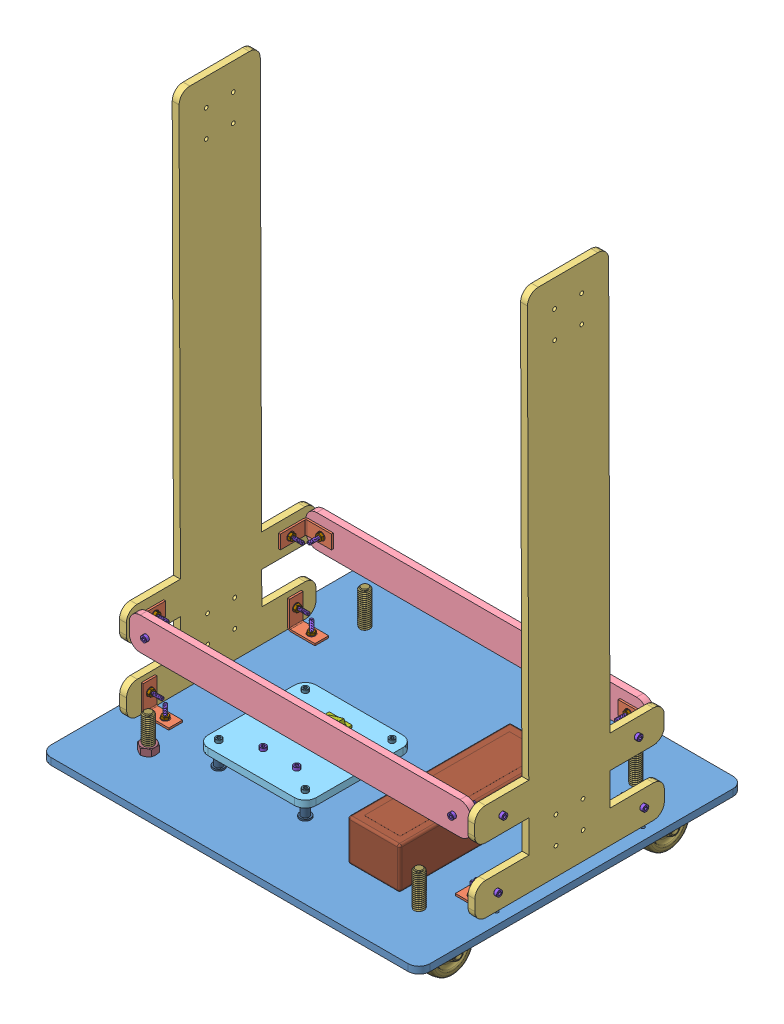
SolidWorks assembly Assembly_bottom, configuration Default. Lengths in mm.
Overall size (350 542.4 300).
72 component instances, 14 part files, 86 mates.
Components (placement in the parent):
- Base-1: Base [Default] at (92.1268 196.2606 279.7334) size (350 6.35 300)
- 1556A410_BRACKET-1: 1556A410_BRACKET [1556A41] at (-65.5682 202.6106 212.2334) x (1 0 0) z (0 1 0) size (25.4 12.7 25.4)
- 1556A410_BRACKET-2: 1556A410_BRACKET [1556A41] at (-65.5682 202.6106 347.2334) x (1 0 0) z (0 1 0) size (25.4 12.7 25.4)
- 1556A410_BRACKET-3: 1556A410_BRACKET [1556A41] at (249.8218 202.6106 212.2334) x (-1 0 0) z (0 1 0) size (25.4 12.7 25.4)
- 1556A410_BRACKET-4: 1556A410_BRACKET [1556A41] at (249.8218 202.6106 347.2334) x (-1 0 0) z (0 1 0) size (25.4 12.7 25.4)
- Part3-1: Part3 [Default] at (-71.9182 442.8211 280.453) x (0 -0.999995 -0.003209) z (0 -0.003209 0.999995) size (480 6.35 175)
- Part3-2: Part3 [Default] at (256.1718 442.8211 280.453) x (0 -0.999995 -0.003209) z (0 0.003209 -0.999995) size (480 6.35 175)
- 1556A410_BRACKET-5: 1556A410_BRACKET [1556A41] at (-65.5682 278.0225 201.5488) size (25.4 12.7 25.4)
- 1556A410_BRACKET-8: 1556A410_BRACKET [1556A41] at (-65.5682 277.6213 358.2981) x (1 0 0) z (0 0 -1) size (25.4 12.7 25.4)
- 1556A410_BRACKET-9: 1556A410_BRACKET [1556A41] at (249.8218 277.6213 358.2981) x (-1 0 0) z (0 0 -1) size (25.4 12.7 25.4)
- 1556A410_BRACKET-10: 1556A410_BRACKET [1556A41] at (249.8218 278.0225 201.5488) x (0 0 1) z (-1 0 0) size (25.4 12.7 25.4)
- Part4-1: Part4 [Default] at (92.1318 278.0225 201.5488) x (1 0 0) z (0 1 0) size (315.39 6.35 30)
- Part4-3: Part4 [Default] at (92.1318 277.6213 358.2981) x (1 0 0) z (0 -1 0) size (315.39 6.35 30)
- Circuit_base-3: Circuit_base [Default] at (52.1268 216.6106 319.7334) size (100 6.35 100)
- circuit-1: circuit [Default] at (54.6268 216.6106 330.2334) x (-1 0 0) z (0 0 1) size (36 3 36)
- switch-2: switch [Default] at (52.2268 222.9606 294.7334) size (21.2 26.4 15.1)
- 91290A123_BLACK-OXIDE CLASS 12.9 SOCKET HEAD CAP SCREW-1: 91290A123_BLACK-OXIDE CLASS 12.9 SOCKET HEAD CAP SCREW [91290A123] at (-51.9182 218.4856 347.2334) x (0 0 -1) z (1 0 0) size (5.5 5.5 23.27)
- 91290A123_BLACK-OXIDE CLASS 12.9 SOCKET HEAD CAP SCREW-2: 91290A123_BLACK-OXIDE CLASS 12.9 SOCKET HEAD CAP SCREW [91290A123] at (-51.9182 218.9188 212.2341) x (0 0 -1) z (1 0 0) size (5.5 5.5 23.27)
- 91290A123_BLACK-OXIDE CLASS 12.9 SOCKET HEAD CAP SCREW-3: 91290A123_BLACK-OXIDE CLASS 12.9 SOCKET HEAD CAP SCREW [91290A123] at (236.1718 218.4856 347.2334) x (0 0 1) z (-1 0 0) size (5.5 5.5 23.27)
- 91290A123_BLACK-OXIDE CLASS 12.9 SOCKET HEAD CAP SCREW-6: 91290A123_BLACK-OXIDE CLASS 12.9 SOCKET HEAD CAP SCREW [91290A123] at (236.1718 218.9188 212.2341) x (0 0 1) z (-1 0 0) size (5.5 5.5 23.27)
- 91290A123_BLACK-OXIDE CLASS 12.9 SOCKET HEAD CAP SCREW-7: 91290A123_BLACK-OXIDE CLASS 12.9 SOCKET HEAD CAP SCREW [91290A123] at (233.9468 216.2606 347.2334) x (-0.837169 0 -0.546944) z (0 1 0) size (5.5 5.5 23.27)
- 91290A123_BLACK-OXIDE CLASS 12.9 SOCKET HEAD CAP SCREW-8: 91290A123_BLACK-OXIDE CLASS 12.9 SOCKET HEAD CAP SCREW [91290A123] at (233.9468 216.2606 212.2334) x (-0.837169 0 -0.546944) z (0 1 0) size (5.5 5.5 23.27)
- 91290A123_BLACK-OXIDE CLASS 12.9 SOCKET HEAD CAP SCREW-9: 91290A123_BLACK-OXIDE CLASS 12.9 SOCKET HEAD CAP SCREW [91290A123] at (-49.6932 216.2606 347.2334) x (-0.837169 0 -0.546944) z (0 1 0) size (5.5 5.5 23.27)
- 91290A123_BLACK-OXIDE CLASS 12.9 SOCKET HEAD CAP SCREW-10: 91290A123_BLACK-OXIDE CLASS 12.9 SOCKET HEAD CAP SCREW [91290A123] at (-49.6932 216.2606 212.2334) x (-0.837169 0 -0.546944) z (0 1 0) size (5.5 5.5 23.27)
- 91290A123_BLACK-OXIDE CLASS 12.9 SOCKET HEAD CAP SCREW-11: 91290A123_BLACK-OXIDE CLASS 12.9 SOCKET HEAD CAP SCREW [91290A123] at (-49.6832 278.0225 215.1988) size (5.5 5.5 23.27)
- 91290A123_BLACK-OXIDE CLASS 12.9 SOCKET HEAD CAP SCREW-13: 91290A123_BLACK-OXIDE CLASS 12.9 SOCKET HEAD CAP SCREW [91290A123] at (233.9568 278.0225 215.1988) size (5.5 5.5 23.27)
- 91290A123_BLACK-OXIDE CLASS 12.9 SOCKET HEAD CAP SCREW-14: 91290A123_BLACK-OXIDE CLASS 12.9 SOCKET HEAD CAP SCREW [91290A123] at (233.9468 277.6213 344.6481) x (1 0 0) z (0 0 -1) size (5.5 5.5 23.27)
- 91290A123_BLACK-OXIDE CLASS 12.9 SOCKET HEAD CAP SCREW-15: 91290A123_BLACK-OXIDE CLASS 12.9 SOCKET HEAD CAP SCREW [91290A123] at (-49.6932 277.6213 344.6481) x (1 0 0) z (0 0 -1) size (5.5 5.5 23.27)
- 91290A123_BLACK-OXIDE CLASS 12.9 SOCKET HEAD CAP SCREW-16: 91290A123_BLACK-OXIDE CLASS 12.9 SOCKET HEAD CAP SCREW [91290A123] at (-51.9182 278.0225 217.4238) x (0 0 -1) z (1 0 0) size (5.5 5.5 23.27)
- 91290A123_BLACK-OXIDE CLASS 12.9 SOCKET HEAD CAP SCREW-17: 91290A123_BLACK-OXIDE CLASS 12.9 SOCKET HEAD CAP SCREW [91290A123] at (-51.9182 277.6213 342.4231) x (0 0 -1) z (1 0 0) size (5.5 5.5 23.27)
- 91290A123_BLACK-OXIDE CLASS 12.9 SOCKET HEAD CAP SCREW-18: 91290A123_BLACK-OXIDE CLASS 12.9 SOCKET HEAD CAP SCREW [91290A123] at (236.1718 277.6213 342.4231) x (0 0 -1) z (-1 0 0) size (5.5 5.5 23.27)
- 91290A123_BLACK-OXIDE CLASS 12.9 SOCKET HEAD CAP SCREW-19: 91290A123_BLACK-OXIDE CLASS 12.9 SOCKET HEAD CAP SCREW [91290A123] at (236.1718 278.0225 217.4238) x (0 0 -1) z (-1 0 0) size (5.5 5.5 23.27)
- 92497A200_ZINC YELLOW-CHROMATE PLATED STEEL HEX NUT-2: 92497A200_ZINC YELLOW-CHROMATE PLATED STEEL HEX NUT [92497A200] at (-49.6932 278.0225 204.5268) size (5.5 6.35 2.78)
- 92497A200_ZINC YELLOW-CHROMATE PLATED STEEL HEX NUT-3: 92497A200_ZINC YELLOW-CHROMATE PLATED STEEL HEX NUT [92497A200] at (234.1068 278.0225 204.5268) size (5.5 6.35 2.78)
- 92497A200_ZINC YELLOW-CHROMATE PLATED STEEL HEX NUT-4: 92497A200_ZINC YELLOW-CHROMATE PLATED STEEL HEX NUT [92497A200] at (233.9468 277.6213 355.3201) size (5.5 6.35 2.78)
- 92497A200_ZINC YELLOW-CHROMATE PLATED STEEL HEX NUT-5: 92497A200_ZINC YELLOW-CHROMATE PLATED STEEL HEX NUT [92497A200] at (-49.8532 277.6213 355.3201) size (5.5 6.35 2.78)
- 92497A200_ZINC YELLOW-CHROMATE PLATED STEEL HEX NUT-7: 92497A200_ZINC YELLOW-CHROMATE PLATED STEEL HEX NUT [92497A200] at (-49.6932 205.5886 347.2334) x (0.837169 0 0.546944) z (0 1 0) size (5.5 6.35 2.78)
- 92497A200_ZINC YELLOW-CHROMATE PLATED STEEL HEX NUT-8: 92497A200_ZINC YELLOW-CHROMATE PLATED STEEL HEX NUT [92497A200] at (-49.6932 205.5886 212.2334) x (0.837169 0 0.546944) z (0 1 0) size (5.5 6.35 2.78)
- 92497A200_ZINC YELLOW-CHROMATE PLATED STEEL HEX NUT-9: 92497A200_ZINC YELLOW-CHROMATE PLATED STEEL HEX NUT [92497A200] at (233.9468 205.5886 347.2334) x (-0.837169 0 -0.546944) z (0 1 0) size (5.5 6.35 2.78)
- 92497A200_ZINC YELLOW-CHROMATE PLATED STEEL HEX NUT-11: 92497A200_ZINC YELLOW-CHROMATE PLATED STEEL HEX NUT [92497A200] at (233.9468 205.5886 212.2334) x (-0.837169 0 -0.546944) z (0 1 0) size (5.5 6.35 2.78)
- 92497A200_ZINC YELLOW-CHROMATE PLATED STEEL HEX NUT-12: 92497A200_ZINC YELLOW-CHROMATE PLATED STEEL HEX NUT [92497A200] at (-62.5902 218.4856 212.2334) x (0 0.381849 -0.924225) z (1 0 0) size (5.5 6.35 2.78)
- 92497A200_ZINC YELLOW-CHROMATE PLATED STEEL HEX NUT-13: 92497A200_ZINC YELLOW-CHROMATE PLATED STEEL HEX NUT [92497A200] at (-62.5902 218.4856 347.2334) x (0 0.381849 -0.924225) z (1 0 0) size (5.5 6.35 2.78)
- 92497A200_ZINC YELLOW-CHROMATE PLATED STEEL HEX NUT-14: 92497A200_ZINC YELLOW-CHROMATE PLATED STEEL HEX NUT [92497A200] at (246.8438 277.6213 342.4231) x (0 1 0) z (-1 0 0) size (5.5 6.35 2.78)
- 92497A200_ZINC YELLOW-CHROMATE PLATED STEEL HEX NUT-15: 92497A200_ZINC YELLOW-CHROMATE PLATED STEEL HEX NUT [92497A200] at (-62.5902 277.6213 342.4231) x (0 0 -1) z (1 0 0) size (5.5 6.35 2.78)
- 92497A200_ZINC YELLOW-CHROMATE PLATED STEEL HEX NUT-16: 92497A200_ZINC YELLOW-CHROMATE PLATED STEEL HEX NUT [92497A200] at (-62.5902 278.0225 217.4238) x (0 0 -1) z (1 0 0) size (5.5 6.35 2.78)
- 92497A200_ZINC YELLOW-CHROMATE PLATED STEEL HEX NUT-17: 92497A200_ZINC YELLOW-CHROMATE PLATED STEEL HEX NUT [92497A200] at (246.8438 278.0225 217.4238) x (0 1 0) z (-1 0 0) size (5.5 6.35 2.78)
- 91290A123_BLACK-OXIDE CLASS 12.9 SOCKET HEAD CAP SCREW-20: 91290A123_BLACK-OXIDE CLASS 12.9 SOCKET HEAD CAP SCREW [91290A123] at (39.1268 202.9606 345.7334) x (1 0 0) z (0 -1 0) size (5.5 5.5 23.27)
- 92497A200_ZINC YELLOW-CHROMATE PLATED STEEL HEX NUT-22: 92497A200_ZINC YELLOW-CHROMATE PLATED STEEL HEX NUT [92497A200] at (39.1268 214.4106 345.7334) x (1 0 0) z (0 -1 0) size (5.5 6.35 2.78)
- 91290A123_BLACK-OXIDE CLASS 12.9 SOCKET HEAD CAP SCREW-21: 91290A123_BLACK-OXIDE CLASS 12.9 SOCKET HEAD CAP SCREW [91290A123] at (70.1268 202.9606 345.7334) x (1 0 0) z (0 -1 0) size (5.5 5.5 23.27)
- 91290A123_BLACK-OXIDE CLASS 12.9 SOCKET HEAD CAP SCREW-22: 91290A123_BLACK-OXIDE CLASS 12.9 SOCKET HEAD CAP SCREW [91290A123] at (39.1268 202.9606 314.7334) x (1 0 0) z (0 -1 0) size (5.5 5.5 23.27)
- 91290A123_BLACK-OXIDE CLASS 12.9 SOCKET HEAD CAP SCREW-23: 91290A123_BLACK-OXIDE CLASS 12.9 SOCKET HEAD CAP SCREW [91290A123] at (70.1268 202.9606 314.7334) x (1 0 0) z (0 -1 0) size (5.5 5.5 23.27)
- 92497A200_ZINC YELLOW-CHROMATE PLATED STEEL HEX NUT-23: 92497A200_ZINC YELLOW-CHROMATE PLATED STEEL HEX NUT [92497A200] at (70.1268 214.4106 345.7334) x (1 0 0) z (0 -1 0) size (5.5 6.35 2.78)
- 92497A200_ZINC YELLOW-CHROMATE PLATED STEEL HEX NUT-24: 92497A200_ZINC YELLOW-CHROMATE PLATED STEEL HEX NUT [92497A200] at (39.1268 214.4106 314.7334) x (1 0 0) z (0 -1 0) size (5.5 6.35 2.78)
- 92497A200_ZINC YELLOW-CHROMATE PLATED STEEL HEX NUT-25: 92497A200_ZINC YELLOW-CHROMATE PLATED STEEL HEX NUT [92497A200] at (70.1268 214.4106 314.7334) x (1 0 0) z (0 -1 0) size (5.5 6.35 2.78)
- circuit_base_spacer-5: circuit_base_spacer [Default] at (12.1268 202.6106 359.7334) size (10 14 10)
- circuit_base_spacer-6: circuit_base_spacer [Default] at (12.1268 202.6106 279.7334) size (10 14 10)
- circuit_base_spacer-7: circuit_base_spacer [Default] at (92.1268 202.6106 359.7334) size (10 14 10)
- circuit_base_spacer-8: circuit_base_spacer [Default] at (92.1268 202.6106 279.7334) size (10 14 10)
- battery-2: battery [Default] at (172.8881 202.6106 302.4714) x (0 0 -1) z (1 0 0) size (150 38.05 48)
- 2834T110_THREADED-STEM SWIVEL CASTER-2: 2834T110_THREADED-STEM SWIVEL CASTER [2834T11] at (-32.8732 215.3106 379.7334) x (0 0 -1) z (1 0 0) size (58.52 93.93 32.91)
- 2834T110_THREADED-STEM SWIVEL CASTER-3: 2834T110_THREADED-STEM SWIVEL CASTER [2834T11] at (217.1268 215.3106 379.7334) x (0 0 -1) z (1 0 0) size (58.52 93.93 32.91)
- 2834T110_THREADED-STEM SWIVEL CASTER-4: 2834T110_THREADED-STEM SWIVEL CASTER [2834T11] at (-32.8732 215.3106 179.7334) x (0 0 -1) z (1 0 0) size (58.52 93.93 32.91)
- 2834T110_THREADED-STEM SWIVEL CASTER-5: 2834T110_THREADED-STEM SWIVEL CASTER [2834T11] at (217.1268 215.3106 179.7334) x (0 0 -1) z (1 0 0) size (58.52 93.93 32.91)
- 90591A161_ZINC PLATED STEEL HEX NUT-1: 90591A161_ZINC PLATED STEEL HEX NUT [90591A161] at (-32.8732 205.8606 379.7334) x (1 0 0) z (0 -1 0) size (13 15.01 7.38)
- 91290A171_BLACK-OXIDE CLASS 12.9 SOCKET HEAD CAP SCREW-5: 91290A171_BLACK-OXIDE CLASS 12.9 SOCKET HEAD CAP SCREW [91290A171] at (12.1268 192.9606 359.7334) x (1 0 0) z (0 -1 0) size (5.5 5.5 33.33)
- 91290A171_BLACK-OXIDE CLASS 12.9 SOCKET HEAD CAP SCREW-6: 91290A171_BLACK-OXIDE CLASS 12.9 SOCKET HEAD CAP SCREW [91290A171] at (92.1268 192.9606 359.7334) x (1 0 0) z (0 -1 0) size (5.5 5.5 33.33)
- 91290A171_BLACK-OXIDE CLASS 12.9 SOCKET HEAD CAP SCREW-7: 91290A171_BLACK-OXIDE CLASS 12.9 SOCKET HEAD CAP SCREW [91290A171] at (12.1268 192.9606 279.7334) x (1 0 0) z (0 -1 0) size (5.5 5.5 33.33)
- 91290A171_BLACK-OXIDE CLASS 12.9 SOCKET HEAD CAP SCREW-8: 91290A171_BLACK-OXIDE CLASS 12.9 SOCKET HEAD CAP SCREW [91290A171] at (92.1268 192.9606 279.7334) x (1 0 0) z (0 -1 0) size (5.5 5.5 33.33)
- 92497A200_ZINC YELLOW-CHROMATE PLATED STEEL HEX NUT-28: 92497A200_ZINC YELLOW-CHROMATE PLATED STEEL HEX NUT [92497A200] at (12.1268 195.0606 359.7334) x (0.837169 0 0.546944) z (0 1 0) size (5.5 6.35 2.78)
- 92497A200_ZINC YELLOW-CHROMATE PLATED STEEL HEX NUT-29: 92497A200_ZINC YELLOW-CHROMATE PLATED STEEL HEX NUT [92497A200] at (92.1268 195.0606 359.7334) x (0.837169 0 0.546944) z (0 1 0) size (5.5 6.35 2.78)
- 92497A200_ZINC YELLOW-CHROMATE PLATED STEEL HEX NUT-30: 92497A200_ZINC YELLOW-CHROMATE PLATED STEEL HEX NUT [92497A200] at (12.1268 195.0606 279.7334) x (0.837169 0 0.546944) z (0 1 0) size (5.5 6.35 2.78)
- 92497A200_ZINC YELLOW-CHROMATE PLATED STEEL HEX NUT-31: 92497A200_ZINC YELLOW-CHROMATE PLATED STEEL HEX NUT [92497A200] at (92.1268 195.0606 279.7334) x (0.837169 0 0.546944) z (0 1 0) size (5.5 6.35 2.78)
Mates (geometry in assembly coordinates):
- Concentric1: concentric anti-aligned: circle of Base-1; circle of 1556A410_BRACKET-1
- Coincident1: coincident anti-aligned: plane of Base-1 through (92.1268 202.6106 279.7334) normal (0 1 0); plane of 1556A410_BRACKET-1 through (-62.9012 202.6106 205.8834) normal (0 -1 0)
- Concentric2: concentric anti-aligned: circle of Base-1; circle of 1556A410_BRACKET-2
- Coincident2: coincident anti-aligned: plane of Base-1 through (92.1268 202.6106 279.7334) normal (0 1 0); plane of 1556A410_BRACKET-2 through (-62.9012 202.6106 340.8834) normal (0 -1 0)
- Concentric3: concentric anti-aligned: circle of Base-1; circle of 1556A410_BRACKET-3
- Parallel1: parallel aligned: plane of Base-1 through (267.1268 202.6106 429.7334) normal (1 0 0); plane of 1556A410_BRACKET-3 through (249.8218 228.0106 218.5834) normal (1 0 0)
- Coincident4: coincident anti-aligned: plane of Base-1 through (92.1268 202.6106 279.7334) normal (0 1 0); plane of 1556A410_BRACKET-3 through (247.1548 202.6106 218.5834) normal (0 -1 0)
- Concentric6: concentric anti-aligned: circle of Base-1; circle of 1556A410_BRACKET-4
- Parallel2: parallel aligned: plane of Base-1 through (267.1268 202.6106 429.7334) normal (1 0 0); plane of 1556A410_BRACKET-4 through (249.8218 228.0106 353.5834) normal (1 0 0)
- Coincident6: coincident anti-aligned: plane of Base-1 through (92.1268 202.6106 279.7334) normal (0 1 0); plane of 1556A410_BRACKET-4 through (247.1548 202.6106 353.5834) normal (0 -1 0)
- Coincident7: coincident anti-aligned: plane of 1556A410_BRACKET-2 through (-65.5682 228.0106 340.8834) normal (-1 0 0); plane of Part3-1 through (-65.5682 442.8211 280.453) normal (1 0 0)
- Concentric7: concentric aligned: circle of 1556A410_BRACKET-2; circle of Part3-1
- Coincident8: coincident anti-aligned: plane of 1556A410_BRACKET-4 through (249.8218 228.0106 353.5834) normal (1 0 0); plane of Part3-2 through (249.8218 442.8211 280.453) normal (-1 0 0)
- Concentric8: concentric aligned: circle of 1556A410_BRACKET-4; circle of Part3-2
- Concentric9: concentric aligned: circle of Part3-1; circle of 1556A410_BRACKET-5
- Coincident19: coincident anti-aligned: plane of Part3-1 through (-65.5682 442.8211 280.453) normal (1 0 0); plane of 1556A410_BRACKET-5 through (-65.5682 284.3725 226.9488) normal (-1 0 0)
- Concentric12: concentric aligned: circle of Part3-1; circle of 1556A410_BRACKET-8
- Coincident25: coincident anti-aligned: plane of Part3-1 through (-65.5682 442.8211 280.453) normal (1 0 0); plane of 1556A410_BRACKET-8 through (-65.5682 271.2713 332.8981) normal (-1 0 0)
- Concentric13: concentric aligned: circle of Part3-2; circle of 1556A410_BRACKET-9
- Coincident28: coincident anti-aligned: plane of Part3-2 through (249.8218 442.8211 280.453) normal (-1 0 0); plane of 1556A410_BRACKET-9 through (249.8218 283.9713 332.8981) normal (1 0 0)
- Concentric14: concentric aligned: circle of Part3-2; circle of 1556A410_BRACKET-10
- Coincident29: coincident anti-aligned: plane of Part3-2 through (249.8218 442.8211 280.453) normal (-1 0 0); plane of 1556A410_BRACKET-10 through (249.8218 284.3725 204.2158) normal (1 0 0)
- Concentric15: concentric anti-aligned: circle of 1556A410_BRACKET-10; circle of Part4-1
- Coincident30: coincident anti-aligned: plane of 1556A410_BRACKET-10 through (224.4218 284.3725 201.5488) normal (0 0 -1); plane of Part4-1 through (92.1318 278.0225 201.5488) normal (0 0 1)
- Concentric16: concentric anti-aligned: circle of Part4-3; circle of 1556A410_BRACKET-9
- Coincident33: coincident anti-aligned: plane of 1556A410_BRACKET-8 through (-62.9012 271.2713 358.2981) normal (0 0 1); plane of Part4-3 through (92.1318 277.6213 358.2981) normal (0 0 -1)
- Concentric18: concentric anti-aligned: circle of 1556A410_BRACKET-9; circle of Part4-3
- Coincident34: coincident anti-aligned: plane of Base-1 through (92.1268 202.6106 279.7334) normal (0 1 0); plane of ? through (22.848 202.6106 279.8388) normal (0 -1 0)
- Coincident35: coincident anti-aligned: circle of ?; circle of Circuit_base-3
- Concentric20: concentric aligned: circle of Circuit_base-3; circle of circuit-1
- Coincident38: coincident: line of Circuit_base-3 through (12.1268 216.6106 369.7334) axis (1 0 0); plane of circuit-1 through (54.6268 216.6106 330.2334) normal (0 1 0)
- Coincident39: coincident anti-aligned: plane of Circuit_base-3 through (52.1268 222.9606 319.7334) normal (0 1 0); plane of switch-2 through (52.2268 222.9606 294.7334) normal (0 -1 0)
- Coincident40: coincident anti-aligned: plane of Circuit_base-3 through (61.6268 222.9606 288.2334) normal (-1 0 0); plane of switch-2 through (61.6268 211.8606 301.2334) normal (1 0 0)
- Coincident41: coincident anti-aligned: plane of Circuit_base-3 through (42.6268 222.9606 301.2334) normal (0 0 -1); plane of switch-2 through (42.8268 211.8606 301.2334) normal (0 0 1)
- Coincident42: coincident aligned: circle of Part3-1; plane of 91290A123_BLACK-OXIDE CLASS 12.9 SOCKET HEAD CAP SCREW-1 through (-71.9182 218.4856 347.2334) normal (1 0 0)
- Concentric21: concentric aligned: circle of Part3-1; circle of 91290A123_BLACK-OXIDE CLASS 12.9 SOCKET HEAD CAP SCREW-1
- Concentric22: concentric anti-aligned: circle of Part3-2; circle of 91290A123_BLACK-OXIDE CLASS 12.9 SOCKET HEAD CAP SCREW-3
- Coincident43: coincident aligned: circle of Part3-2; plane of 91290A123_BLACK-OXIDE CLASS 12.9 SOCKET HEAD CAP SCREW-3 through (256.1718 218.4856 347.2334) normal (-1 0 0)
- Coincident44: coincident anti-aligned: circle of Base-1; plane of 91290A123_BLACK-OXIDE CLASS 12.9 SOCKET HEAD CAP SCREW-7 through (233.9468 196.2606 347.2334) normal (0 1 0)
- Concentric28: concentric aligned: circle of Base-1; circle of 91290A123_BLACK-OXIDE CLASS 12.9 SOCKET HEAD CAP SCREW-7
- Concentric29: concentric anti-aligned: circle of Part4-1; circle of 91290A123_BLACK-OXIDE CLASS 12.9 SOCKET HEAD CAP SCREW-11
- Coincident45: coincident anti-aligned: plane of Part4-1 through (92.1318 278.0225 195.1988) normal (0 0 -1); plane of 91290A123_BLACK-OXIDE CLASS 12.9 SOCKET HEAD CAP SCREW-11 through (-49.6832 278.0225 195.1988) normal (0 0 1)
- Concentric30: concentric aligned: circle of Part4-3; circle of 91290A123_BLACK-OXIDE CLASS 12.9 SOCKET HEAD CAP SCREW-14
- Coincident46: coincident anti-aligned: plane of Part4-3 through (92.1318 277.6213 364.6481) normal (0 0 1); plane of 91290A123_BLACK-OXIDE CLASS 12.9 SOCKET HEAD CAP SCREW-14 through (233.9468 277.6213 364.6481) normal (0 0 -1)
- Coincident48: coincident aligned: circle of Part3-1; plane of 91290A123_BLACK-OXIDE CLASS 12.9 SOCKET HEAD CAP SCREW-16 through (-71.9182 278.0225 217.4238) normal (1 0 0)
- Concentric32: concentric aligned: circle of Part3-2; circle of 91290A123_BLACK-OXIDE CLASS 12.9 SOCKET HEAD CAP SCREW-18
- Coincident49: coincident aligned: circle of Part3-2; plane of 91290A123_BLACK-OXIDE CLASS 12.9 SOCKET HEAD CAP SCREW-18 through (256.1718 277.6213 342.4231) normal (-1 0 0)
- Coincident50: coincident anti-aligned: plane of 1556A410_BRACKET-5 through (-62.9012 284.3725 203.3268) normal (0 0 1); plane of 92497A200_ZINC YELLOW-CHROMATE PLATED STEEL HEX NUT-2 through (-52.4432 279.6102 203.3268) normal (0 0 -1)
- Coincident51: coincident anti-aligned: circle of 1556A410_BRACKET-5; plane of 92497A200_ZINC YELLOW-CHROMATE PLATED STEEL HEX NUT-2 through (-52.4432 279.6102 203.3268) normal (0 0 -1)
- Concentric33: concentric anti-aligned: circle of 1556A410_BRACKET-5; circle of 92497A200_ZINC YELLOW-CHROMATE PLATED STEEL HEX NUT-2
- Coincident52: coincident anti-aligned: plane of 1556A410_BRACKET-9 through (247.1548 283.9713 356.5201) normal (0 0 -1); plane of 92497A200_ZINC YELLOW-CHROMATE PLATED STEEL HEX NUT-4 through (231.1968 279.209 356.5201) normal (0 0 1)
- Concentric34: concentric anti-aligned: circle of 1556A410_BRACKET-9; circle of 92497A200_ZINC YELLOW-CHROMATE PLATED STEEL HEX NUT-4
- Coincident53: coincident anti-aligned: plane of 1556A410_BRACKET-2 through (-62.9012 204.3886 340.8834) normal (0 1 0); plane of 92497A200_ZINC YELLOW-CHROMATE PLATED STEEL HEX NUT-7 through (-51.127 204.3886 344.4001) normal (0 -1 0)
- Concentric36: concentric anti-aligned: circle of 1556A410_BRACKET-2; circle of 92497A200_ZINC YELLOW-CHROMATE PLATED STEEL HEX NUT-7
- Coincident54: coincident anti-aligned: plane of 1556A410_BRACKET-4 through (247.1548 204.3886 353.5834) normal (0 1 0); plane of 92497A200_ZINC YELLOW-CHROMATE PLATED STEEL HEX NUT-9 through (235.3806 204.3886 350.0667) normal (0 -1 0)
- Concentric38: concentric aligned: circle of 1556A410_BRACKET-4; circle of 92497A200_ZINC YELLOW-CHROMATE PLATED STEEL HEX NUT-9
- Coincident55: coincident anti-aligned: plane of 1556A410_BRACKET-1 through (-63.7902 228.0106 205.8834) normal (1 0 0); plane of 92497A200_ZINC YELLOW-CHROMATE PLATED STEEL HEX NUT-12 through (-63.7902 218.9029 215.3813) normal (-1 0 0)
- Concentric39: concentric aligned: circle of 1556A410_BRACKET-1; circle of 92497A200_ZINC YELLOW-CHROMATE PLATED STEEL HEX NUT-12
- Concentric40: concentric aligned: circle of 1556A410_BRACKET-9; circle of 92497A200_ZINC YELLOW-CHROMATE PLATED STEEL HEX NUT-14
- Coincident58: coincident anti-aligned: plane of 1556A410_BRACKET-9 through (248.0438 283.9713 332.8981) normal (-1 0 0); plane of 92497A200_ZINC YELLOW-CHROMATE PLATED STEEL HEX NUT-14 through (248.0438 274.8713 340.8354) normal (1 0 0)
- Coincident59: coincident anti-aligned: plane of 1556A410_BRACKET-8 through (-63.7902 271.2713 332.8981) normal (1 0 0); plane of 92497A200_ZINC YELLOW-CHROMATE PLATED STEEL HEX NUT-15 through (-63.7902 279.209 345.1731) normal (-1 0 0)
- Concentric41: concentric anti-aligned: circle of 1556A410_BRACKET-8; circle of 92497A200_ZINC YELLOW-CHROMATE PLATED STEEL HEX NUT-15
- Coincident63: coincident anti-aligned: circle of Circuit_base-3; plane of ? through (172.1268 221.6606 359.7334) normal (0 1 0)
- Coincident64: coincident anti-aligned: plane of Base-1 through (92.1268 202.6106 279.7334) normal (0 1 0); plane of circuit_base_spacer-7 through (92.1268 202.6106 359.7334) normal (0 -1 0)
- Concentric42: concentric anti-aligned: circle of Base-1; circle of circuit_base_spacer-7
- Concentric43: concentric anti-aligned: circle of Circuit_base-3; circle of circuit_base_spacer-7
- Coincident65: coincident anti-aligned: circle of Circuit_base-3; plane of circuit_base_spacer-7 through (92.1268 216.6106 359.7334) normal (0 1 0)
- Concentric44: concentric aligned: circle of Part3-1; circle of 91290A123_BLACK-OXIDE CLASS 12.9 SOCKET HEAD CAP SCREW-17
- Coincident66: coincident anti-aligned: plane of Circuit_base-3 through (132.1268 222.9606 319.7334) normal (0 1 0); plane of 91290A171_BLACK-OXIDE CLASS 12.9 SOCKET HEAD CAP SCREW-6 through (92.1268 222.9606 359.7334) normal (0 -1 0)
- Concentric45: concentric aligned: circle of Circuit_base-3; circle of 91290A171_BLACK-OXIDE CLASS 12.9 SOCKET HEAD CAP SCREW-6
- Coincident68: coincident anti-aligned: circle of Base-1; plane of ? through (89.3768 196.2606 361.3211) normal (0 1 0)
- Concentric46: concentric aligned: circle of Base-1; circle of ?
- Coincident69: coincident anti-aligned: plane of Circuit_base-3 through (52.1268 222.9606 319.7334) normal (0 1 0); plane of 91290A123_BLACK-OXIDE CLASS 12.9 SOCKET HEAD CAP SCREW-20 through (39.1268 222.9606 345.7334) normal (0 -1 0)
- Concentric47: concentric aligned: circle of Circuit_base-3; circle of 91290A123_BLACK-OXIDE CLASS 12.9 SOCKET HEAD CAP SCREW-20
- Coincident71: coincident anti-aligned: plane of circuit-1 through (54.6268 215.6106 330.2334) normal (0 -1 0); plane of 92497A200_ZINC YELLOW-CHROMATE PLATED STEEL HEX NUT-22 through (36.3768 215.6106 347.3211) normal (0 1 0)
- Coincident72: coincident anti-aligned: circle of circuit-1; circle of 92497A200_ZINC YELLOW-CHROMATE PLATED STEEL HEX NUT-22
- Concentric48: concentric anti-aligned: circle of Base-1; circle of circuit_base_spacer-5
- Concentric49: concentric anti-aligned: circle of Circuit_base-3; circle of circuit_base_spacer-5
- Coincident75: coincident anti-aligned: plane of Base-1 through (92.1268 202.6106 279.7334) normal (0 1 0); plane of battery-2 through (172.8881 202.6106 302.4714) normal (0 -1 0)
- Coincident76: coincident anti-aligned: circle of Base-1; plane of 2834T110_THREADED-STEM SWIVEL CASTER-2 through (-32.8732 196.2606 391.9952) normal (0 1 0)
- Concentric56: concentric anti-aligned: circle of Base-1; circle of 2834T110_THREADED-STEM SWIVEL CASTER-2
- Concentric57: concentric aligned: circle of 2834T110_THREADED-STEM SWIVEL CASTER-2; circle of 90591A161_ZINC PLATED STEEL HEX NUT-1
- Coincident79: coincident anti-aligned: plane of Circuit_base-3 through (52.1268 222.9606 319.7334) normal (0 1 0); plane of 91290A171_BLACK-OXIDE CLASS 12.9 SOCKET HEAD CAP SCREW-5 through (12.1268 222.9606 359.7334) normal (0 -1 0)
- Concentric59: concentric aligned: circle of Circuit_base-3; circle of 91290A171_BLACK-OXIDE CLASS 12.9 SOCKET HEAD CAP SCREW-5
- Coincident80: coincident anti-aligned: circle of Base-1; plane of 92497A200_ZINC YELLOW-CHROMATE PLATED STEEL HEX NUT-28 through (10.693 196.2606 356.9001) normal (0 1 0)
- Concentric62: concentric anti-aligned: circle of Base-1; circle of 92497A200_ZINC YELLOW-CHROMATE PLATED STEEL HEX NUT-28
